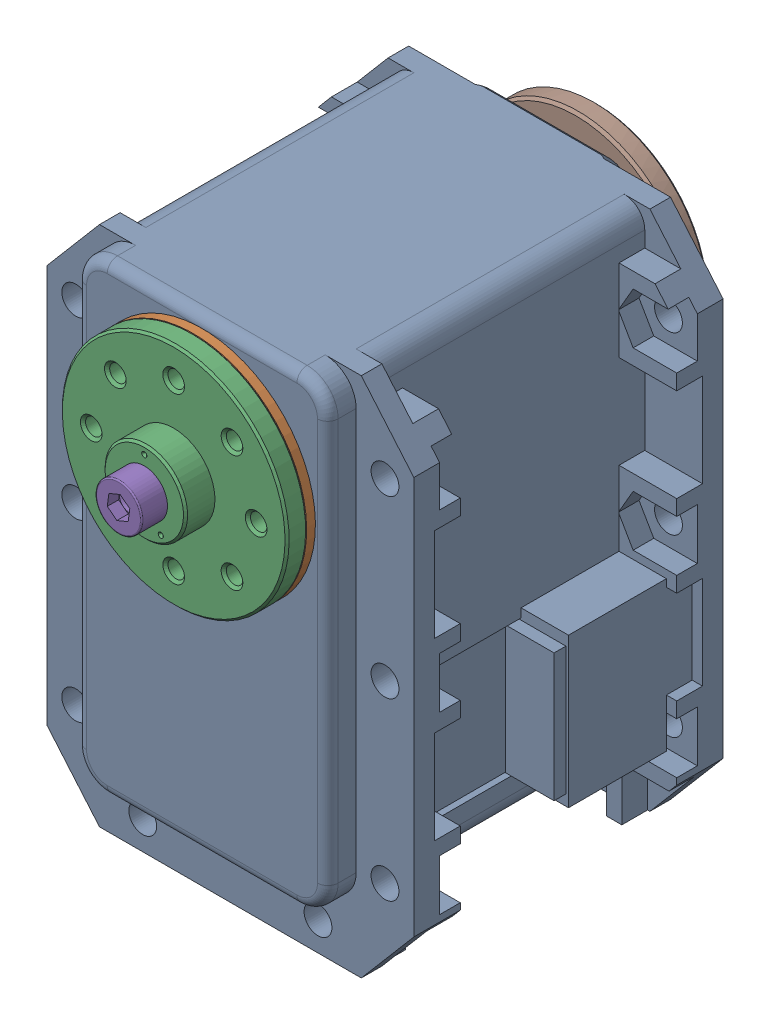
SolidWorks assembly MX-28(U)-10, configuration Default. Lengths in mm.
Overall size (35.6 54.13 48.5).
8 component instances, 7 part files, 0 mates.
Components (placement in the parent):
- dynamixel_x28series(U)-1: dynamixel_x28series(U) [Default] at origin size (35.6 50.71 41.85)
- trust_washer(U)-1: trust_washer(U) [Default] at (0 0 18.6) x (-0.666375 -0.745617 0) z (0.745617 -0.666375 0) size (22 0.85 22)
- HN07-N101(U)-1: HN07-N101(U) [Default] at (0 0 18.5) x (1 0 0) z (0 -1 0) size (22 5.85 22)
- WB_M2.5x8-1: WB_M2.5x8 [Default] at (0 0 -22.65) x (0 0 1) z (-0.936501 0.350665 0) size (10.5 4.5 4.5)
- WB_M2.5x8-2: WB_M2.5x8 [Default] at (0 0 25.85) x (0 0 -1) z (-0.991137 0.132843 0) size (10.5 4.5 4.5)
- RX28-CAP-1: RX28-CAP [Default] at (0 0 -20.35) x (-0.995735 -0.092256 0) z (0 0 -1) size (7.2 7.2 1.8)
- MF106ZZ-1: MF106ZZ [Default] at (0 0 -20.35) x (0.888333 -0.4592 0) z (-0.4592 -0.888333 0) size (11.2 3 11.2)
- HN07-i101-1: HN07-i101 [Default] at (0 0 -20.5) x (1 0 0) z (0 1 0) size (22 3.05 22)
